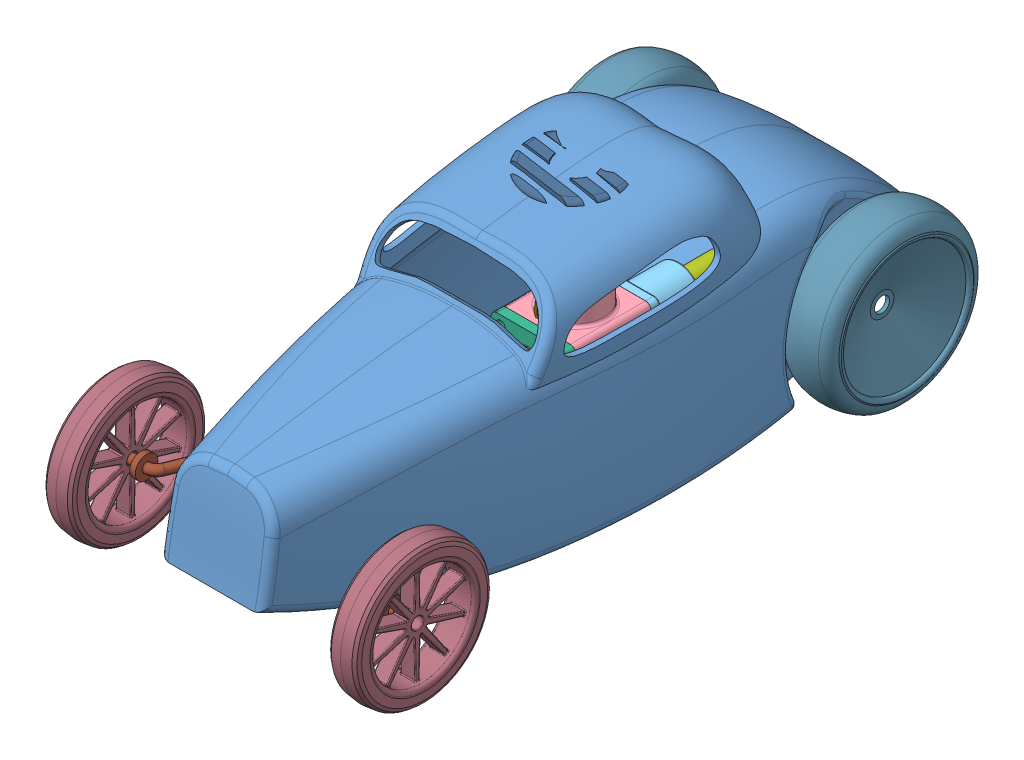
SolidWorks assembly CarAssembly, configuration Default. Lengths in mm.
Overall size (174.43 146.94 348.66).
18 component instances, 14 part files, 18 mates.
Components (placement in the parent):
- body 34 Ford starting model 2019-1: body 34 Ford starting model 2019 [Default] at (274.2675 152.343 85.0893) size (174.41 146.64 341.13)
- FuelTankAssembly-1: FuelTankAssembly [Default] at (416.081 190.343 145.9788) size (52.46 61.37 77.99)
  - 4.1_FuelTankBottom-1: 4.1_FuelTankBottom.prt [Default] at (-141.8134 3.8592 -120.8896) size (52.46 60.61 77.99)
  - 4.0_FuelTankTop-2: 4.0_FuelTankTop.prt [Default] at (-141.8134 32.6593 -149.0555) x (0 0 1) z (-1 0 0) size (58 55 40)
- EngineAssembly-1: EngineAssembly [Default] at (274.2675 172.343 -49.9107) size (63.96 105.81 104.74)
  - Tutorial1-1: Tutorial1 [Default] at (0 15.451 0) size (63.96 90 44)
  - 1_Front-2: 1_Front [Default] at (0 15.451 -20) x (1 0 0) z (0 1 0) size (40 37 40)
  - 2_Rear-1: 2_Rear [Default] at (0 15.451 25) x (-1 0 0) z (0 0 -1) size (40 40 11)
  - 4_Crankshaft-1: 4_Crankshaft [Default] at (-0.0653 15.766 -16.5) x (0 0 1) z (-0.979163 -0.203077 0) size (78 31 31)
  - 3_Piston-1: 3_Piston [Default] at (0 81.5308 14.9822) x (0 0 -1) z (0 -1 0) size (16.08 16.08 18)
  - 5_Conrod-1: 5_Conrod [Default] at (0 56.7479 16.7404) x (0 -0.999998 0.002114) z (0 -0.002114 -0.999998) size (45 11 6)
  - 6_CylinderHead-1: 6_CylinderHead [Default] at (0.0177 100.4164 0) x (0.990295 0 0.138983) z (0.138983 0 -0.990295) size (50.13 23.81 50)
- 2_FrontAxle-2: 2_FrontAxle.prt [Default] at (273.926 182.343 83.8412) x (-1 0 0) z (0 0 -1) size (150 28.5 54.5)
- 3_SuspensionSprings-1: 3_SuspensionSprings.prt [Default] at (274.8678 161.8845 65.2246) size (10.93 36 10.93)
- 1.0_FrontWheel-1: 1.0_FrontWheel [Default] at (354.7059 182.5409 113.8412) x (0 0 -1) z (1 0 0) size (74 74 16)
- 1.1_RearWheel-1: 1.1_RearWheel [Default] at (341.0273 193.8802 -144.9107) x (0 0 -1) z (1 0 0) size (86.98 86.98 29.02)
- 1.1_RearWheel-2: 1.1_RearWheel [Default] at (207.5078 193.8802 -144.9107) x (0 0 1) z (-1 0 0) size (86.98 86.98 29.02)
- 1.0_FrontWheel-2: 1.0_FrontWheel [Default] at (203.4209 182.5409 113.8412) x (0 0 -1) z (1 0 0) size (74 74 16)
Mates (geometry in assembly coordinates):
- Coincident1: coincident: plane of body 34 Ford starting model 2019-1 through (274.2675 152.343 85.0893) normal (1 0 0); plane of FuelTankAssembly-1/4.1_FuelTankBottom-1 through (274.2675 194.2022 25.0893) normal (1 0 0)
- Distance20: distance = 2 mm: plane of FuelTankAssembly-1 through (416.081 190.343 145.9788) normal (0 1 0); plane of assembly through (274.2675 188.343 85.0893) normal (0 1 0)
- Coincident3: coincident: plane of body 34 Ford starting model 2019-1 through (274.2675 152.343 25.0893) normal (0 0 1); plane of FuelTankAssembly-1/4.1_FuelTankBottom-1 through (274.2675 194.2022 25.0893) normal (0 0 1)
- Coincident8: coincident: plane of FuelTankAssembly-1/4.1_FuelTankBottom-1 through (274.2675 194.2022 25.0893) normal (1 0 0); plane of EngineAssembly-1 through (274.2675 172.343 -49.9107) normal (1 0 0)
- Distance1: distance = 20 mm: plane of body 34 Ford starting model 2019-1 through (274.2675 152.343 85.0893) normal (0 1 0); plane of EngineAssembly-1 through (274.2675 172.343 -49.9107) normal (0 1 0)
- Distance2: distance = 75 mm: plane of EngineAssembly-1 through (274.2675 172.343 -49.9107) normal (0 0 1); plane of FuelTankAssembly-1/4.1_FuelTankBottom-1 through (274.2675 194.2022 25.0893) normal (0 0 1)
- Distance3: distance = 66.7598 mm: plane of 1.1_RearWheel-1 through (341.0273 193.8802 -144.9107) normal (1 0 0); plane of EngineAssembly-1 through (274.2675 172.343 -49.9107) normal (1 0 0)
- Distance4: distance = 21.5372 mm: plane of 1.1_RearWheel-1 through (341.0273 193.8802 -144.9107) normal (0 1 0); plane of EngineAssembly-1 through (274.2675 172.343 -49.9107) normal (0 1 0)
- Distance5: distance = 95 mm: plane of 1.1_RearWheel-1 through (341.0273 193.8802 -144.9107) normal (0 0 -1); plane of EngineAssembly-1 through (274.2675 172.343 -49.9107) normal (0 0 1)
- Distance6: distance = 80.4384 mm: plane of 1.0_FrontWheel-1 through (354.7059 182.5409 113.8412) normal (1 0 0); plane of EngineAssembly-1 through (274.2675 172.343 -49.9107) normal (1 0 0)
- Distance7: distance = 10.1979 mm: plane of 1.0_FrontWheel-1 through (354.7059 182.5409 113.8412) normal (0 1 0); plane of EngineAssembly-1 through (274.2675 172.343 -49.9107) normal (0 1 0)
- Distance8: distance = 88.7519 mm: plane of 1.0_FrontWheel-1 through (354.7059 182.5409 113.8412) normal (0 0 -1); plane of FuelTankAssembly-1/4.1_FuelTankBottom-1 through (274.2675 194.2022 25.0893) normal (0 0 1)
- Distance9: distance = 58.7519 mm: plane of 2_FrontAxle-2 through (273.926 182.343 83.8412) normal (0 0 -1); plane of FuelTankAssembly-1/4.1_FuelTankBottom-1 through (274.2675 194.2022 25.0893) normal (0 0 1)
- Distance19: distance = 6 mm: plane of 2_FrontAxle-2 through (273.926 182.343 83.8412) normal (0 1 0); plane of body 34 Ford starting model 2019-1 through (274.2675 188.343 85.0893) normal (0 1 0)
- Distance11: distance = 0.3415 mm: plane of 2_FrontAxle-2 through (273.926 182.343 83.8412) normal (-1 0 0); plane of EngineAssembly-1 through (274.2675 172.343 -49.9107) normal (1 0 0)
- Distance14: distance = 19.8647 mm: plane of body 34 Ford starting model 2019-1 through (274.2675 152.343 85.0893) normal (0 0 1); plane of 3_SuspensionSprings-1 through (274.8678 161.8845 65.2246) normal (0 0 1)
- Distance15: distance = 20.4586 mm: plane of body 34 Ford starting model 2019-1 through (274.2675 182.343 85.0893) normal (0 -1 0); plane of 3_SuspensionSprings-1 through (274.8678 161.8845 65.2246) normal (0 1 0)
- Distance16: distance = 274.8678 mm: plane of assembly through (0 0 0) normal (1 0 0); plane of 3_SuspensionSprings-1 through (274.8678 161.8845 65.2246) normal (1 0 0)
